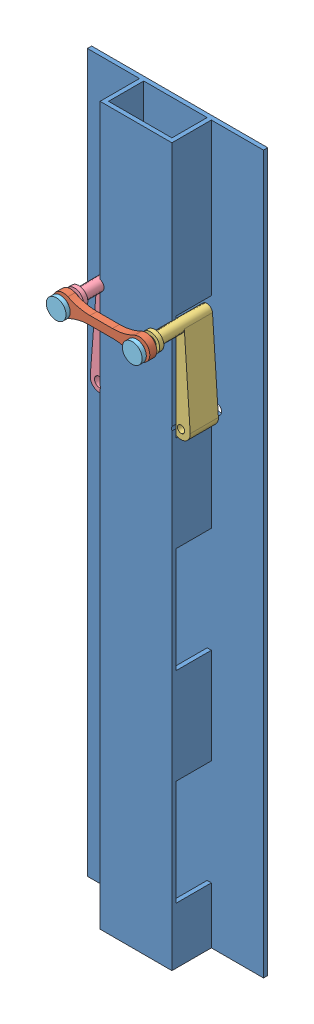
SolidWorks assembly Tubo salida con palancas, configuration Predeterminado. Lengths in mm.
Overall size (125 509 61).
6 component instances, 5 part files, 20 mates.
Components (placement in the parent):
- Tubo de salida-1: Tubo de salida [Predeterminado] at origin size (125 509 31)
- Union-1: Union [Predeterminado] at (0.3162 141.2109 35.5) x (1 0.000375 0) z (0 0 1) size (69 15 5)
- Palanquita der-1: Palanquita der [Predeterminado] at (29 78.6937 2.5) x (-0.013056 -0.999915 0) z (0.999915 -0.013056 0) size (75.5 50 15.5)
- Palanquita izq-1: Palanquita izq [Predeterminado] at (-29 78.6937 2.5) x (0.00294 -0.999996 0) z (-0.999996 -0.00294 0) size (75.5 50 15.5)
- Tapones-1: Tapones [Predeterminado] at (-26.6838 141.2008 39.5) x (1 0 0) z (0 -1 0) size (14 9 14)
- Tapones-2: Tapones [Predeterminado] at (27.3162 141.2211 39.5) x (1 0 0) z (0 -1 0) size (14 9 14)
Mates (geometry in assembly coordinates):
- Coincidente2: coincident aligned: plane of ? through (-33 78.1144 0) normal (0 0 1); plane of assembly through (0 0 0) normal (0 0 1)
- Concéntrica5: concentric aligned: circle of Tubo de salida-1; circle of ?
- Coincidente5: coincident aligned: plane of Tubo de salida-1 through (0 0 0) normal (1 0 0); plane of assembly through (0 0 0) normal (1 0 0)
- Coincidente6: coincident aligned: plane of Tubo de salida-1 through (0 0 0) normal (0 1 0); plane of assembly through (0 0 0) normal (0 1 0)
- Coincidente7: coincident aligned: plane of Tubo de salida-1 through (0 0 0) normal (0 0 1); plane of assembly through (0 0 0) normal (0 0 1)
- Concéntrica7: concentric aligned: circle of Tubo de salida-1; circle of ?
- Concéntrica8: concentric aligned: cylinder of ? through (-27 138.2127 21.5) axis (0 0 1) radius 2.6; circle of Union-1
- Distancia3: distance = 25 mm aligned: plane of ? through (-29 78.6937 12.5) normal (0 0 1); plane of Tubo de salida-1 through (-22.5 254.5 -12.5) normal (0 0 1)
- Distancia4: distance = 10 mm aligned: plane of Union-1 through (7.9671 100.2127 22.5) normal (0 0 1); plane of ? through (-29 78.6937 12.5) normal (0 0 1)
- Concéntrica9: concentric aligned: cylinder of Tubo de salida-1 through (-29 78.6937 -15.5) axis (0 0 1) radius 3.75; cylinder of Palanquita izq-1 through (-29 78.6937 -7.5) axis (0 0 1) radius 3.475
- Concéntrica10: concentric anti-aligned: cylinder of Tubo de salida-1 through (29 78.6937 -15.5) axis (0 0 1) radius 3.75; cylinder of Palanquita der-1 through (29 78.6937 12.5) axis (0 0 -1) radius 2.6
- Concéntrica11: concentric aligned: circle of Union-1; circle of Palanquita izq-1
- Concéntrica12: concentric anti-aligned: cylinder of Union-1 through (27.3162 141.2211 40.5) axis (0 0 -1) radius 4.3; cylinder of Palanquita der-1 through (27.3162 141.2211 -7.5) axis (0 0 1) radius 4
- Distancia6: distance = 3 mm anti-aligned: plane of Union-1 through (8.2976 103.2139 35.5) normal (0 0 -1); plane of Palanquita izq-1 through (-26.6838 141.2008 32.5) normal (0 0 1)
- Distancia7: distance = 25 mm aligned: plane of Palanquita izq-1 through (-29 78.6937 12.5) normal (0 0 1); plane of Tubo de salida-1 through (-22.5 254.5 -12.5) normal (0 0 1)
- Distancia9: distance = 25 mm aligned: plane of Palanquita der-1 through (29 78.6937 12.5) normal (0 0 1); plane of Tubo de salida-1 through (-22.5 254.5 -12.5) normal (0 0 1)
- Concéntrica13: concentric anti-aligned: cylinder of Palanquita izq-1 through (-26.6838 141.2008 32.5) axis (0 0 1) radius 2.6; cylinder of Tapones-1 through (-26.6838 141.2008 42.5) axis (0 0 -1) radius 2.5
- Coincidente8: coincident anti-aligned: plane of Palanquita izq-1 through (-26.6838 141.2008 42.5) normal (0 0 1); plane of Tapones-1 through (-26.6838 141.2008 42.5) normal (0 0 -1)
- Coincidente9: coincident anti-aligned: plane of Palanquita der-1 through (27.3162 141.2211 42.5) normal (0 0 1); plane of Tapones-2 through (27.3162 141.2211 42.5) normal (0 0 -1)
- Concéntrica14: concentric anti-aligned: cylinder of Palanquita der-1 through (27.3162 141.2211 -7.5) axis (0 0 1) radius 4; cylinder of Tapones-2 through (27.3162 141.2211 42.5) axis (0 0 -1) radius 2.5
